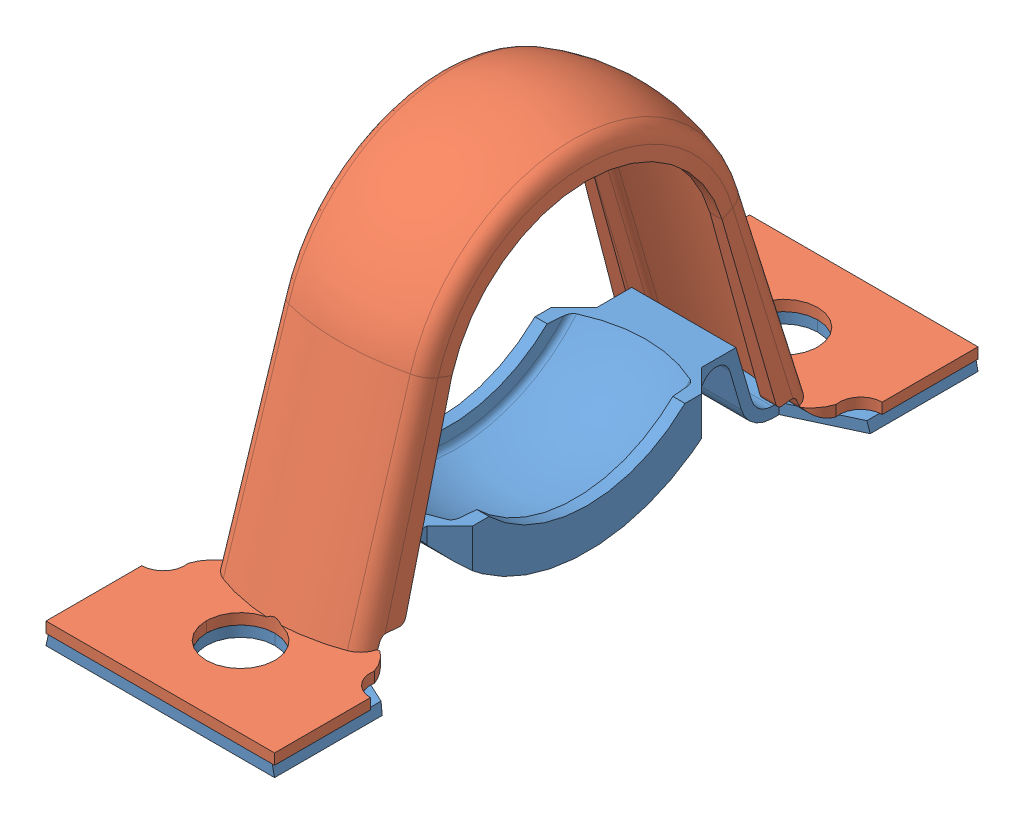
SolidWorks assembly PUTM-S-SS-SC-Bearing_mount-P47, configuration Default. Lengths in mm.
Overall size (32 50.5 98.5).
2 component instances, 2 part files, 0 mates.
Components (placement in the parent):
- PUTM-S-SS-SC-Bearing_mount-P47-Upper-1: PUTM-S-SS-SC-Bearing_mount-P47-Upper [Default] at (0 25.3 0) x (0 0 -1) z (1 0 0) size (98.5 12.2 32)
- PUTM-S-SS-SC-Bearing_mount-P47-Down-1: PUTM-S-SS-SC-Bearing_mount-P47-Down [Default] at (0 25.3 0) x (0 0 -1) z (1 0 0) size (98.5 49.31 32)
